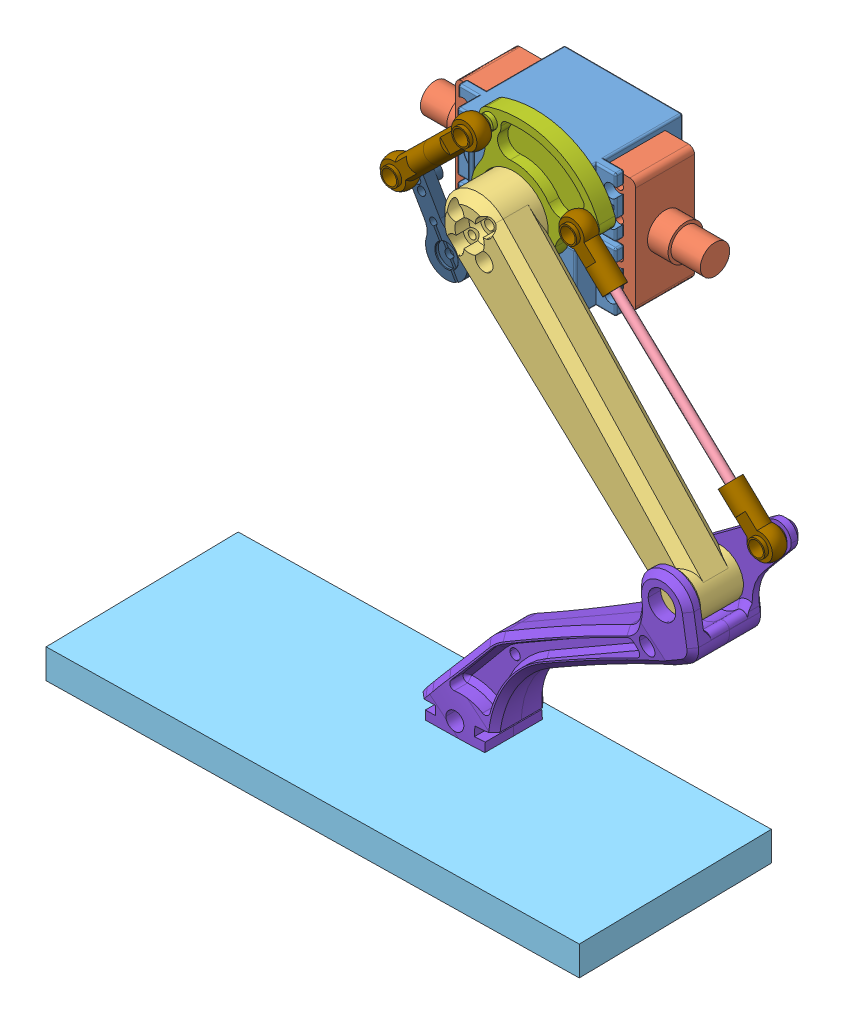
SolidWorks assembly test, configuration Default. Lengths in mm.
Overall size (210.82 208.45 93.67).
15 component instances, 10 part files, 35 mates.
Components (placement in the parent):
- Servo MG996R-1: Servo MG996R [Predeterminado] at (-30.3678 43.9718 31.47) x (1 0 0) z (0 -1 0) size (53.6 47.6 20)
- Servo MG996R-2: Servo MG996R [Predeterminado] at (9.9322 85.9718 31.47) x (-1 0 0) z (0 1 0) size (53.6 47.6 20)
- m_servo_siding-1: m_servo_siding [Default] at (15.4322 64.9718 38.07) size (27 39 20)
- m_servo_siding-2: m_servo_siding [Default] at (-35.8678 64.9718 38.07) x (-1 0 0) z (0 0 1) size (27 39 20)
- upperleg-2: upperleg [Default] at (88.8454 65.1989 5.4511) x (-0.00634 0.283453 0.958965) z (-0.99975 -0.022362 0) size (39.1 93.25 88.61)
- 74_thread-1: 74_thread [Default] at (84.3185 29.4705 82.3546) x (-0.621098 -0.659068 0.424106) z (-0.290865 -0.308647 -0.905613) size (3 74 3)
- Part1^test-1: Part1^test [Default] at (72.6841 -86.0282 -17.0834) x (-0.017436 0 -0.999848) z (0 -1 0) size (66.55 178.4 10) (virtual)
- circular_horn-2: circular_horn [Default] at (-0.0678 75.9718 77.6046) x (-0.859308 -0.511458 0) z (0.511458 -0.859308 0) size (20 4.5 20)
- my_2order-1: my_2order [Default] at (-0.0678 75.9718 70.1746) x (-0.942139 -0.335224 0) z (0 0 1) size (45.25 42.25 10.43)
- lowerleg_r-1: lowerleg_r [Default] at (92.6802 63.8975 4.4511) x (0.011988 0.28327 0.958965) z (-0.999106 0.042282 0) size (46.27 106.28 105.17)
- ball_joint-1: ball_joint [Default] at (89.4129 24.6697 82.3546) x (-0.685832 -0.72776 0) z (0 0 1) size (10 22 7.5)
- ball_joint-2: ball_joint [Default] at (25.37 85.0229 82.3546) x (-0.685832 -0.72776 0) z (0 0 -1) size (10 22 7.5)
- link3_m-1: link3_m [Default] at (85.0271 26.6006 7.1666) x (0.089359 0.269073 0.958965) z (-0.949034 0.315174 0) size (12.82 26.51 28.54)
- ball_joint-3: ball_joint [Default] at (-32.3678 74.7565 85.42) x (0.700786 -0.713371 0) z (0 0 -1) size (10 22 7.5)
- ball_joint-4: ball_joint [Default] at (-8.1131 98.5832 85.42) x (-0.700786 0.713371 0) z (0 0 -1) size (10 22 7.5)
Mates (geometry in assembly coordinates):
- Coincident17: coincident aligned: plane of Servo MG996R-1 through (-6.7057 61.6867 69.07) normal (0 0 1); plane of Servo MG996R-2 through (-13.7299 68.257 69.07) normal (0 0 1)
- Coincident18: coincident aligned: plane of Servo MG996R-1 through (9.9322 43.9718 68.07) normal (1 0 0); plane of Servo MG996R-2 through (9.9322 85.9718 68.07) normal (1 0 0)
- Width3: width anti-aligned: plane of Servo MG996R-2 through (9.9322 65.9718 68.07) normal (0 -1 0); plane of Servo MG996R-1 through (-30.3678 63.9718 68.07) normal (0 1 0); plane of m_servo_siding-1 through (10.4322 84.4718 58.07) normal (0 1 0); plane of m_servo_siding-1 through (10.4322 45.4718 58.07) normal (0 -1 0)
- Coincident19: coincident anti-aligned: plane of Servo MG996R-2 through (16.5822 85.9718 58.07) normal (0 0 -1); plane of m_servo_siding-1 through (18.4322 82.4718 58.07) normal (0 0 1)
- Coincident22: coincident aligned: plane of m_servo_siding-1 through (10.4322 84.4718 58.07) normal (0 1 0); plane of m_servo_siding-2 through (-30.8678 84.4718 58.07) normal (0 1 0)
- Coincident23: coincident aligned: plane of m_servo_siding-1 through (18.4322 82.4718 58.07) normal (0 0 1); plane of m_servo_siding-2 through (-38.8678 47.4718 58.07) normal (0 0 1)
- Concentric16: concentric aligned: cylinder of Servo MG996R-2 through (-35.3678 80.4718 58.07) axis (0 0 1) radius 2.22; cylinder of m_servo_siding-2 through (-35.3678 80.4718 46.07) axis (0 0 1) radius 1.35
- Concentric17: concentric aligned: cylinder of Servo MG996R-1 through (-35.3678 49.4718 58.07) axis (0 0 1) radius 2.22; cylinder of m_servo_siding-2 through (-35.3678 49.4718 46.07) axis (0 0 1) radius 1.35
- Concentric18: concentric aligned: cylinder of Servo MG996R-1 through (14.9322 49.4718 58.07) axis (0 0 1) radius 2.22; cylinder of m_servo_siding-1 through (14.9322 49.4718 46.07) axis (0 0 1) radius 1.35
- Concentric19: concentric aligned: cylinder of Servo MG996R-2 through (14.9322 80.4718 58.07) axis (0 0 1) radius 2.22; cylinder of m_servo_siding-1 through (14.9322 80.4718 46.07) axis (0 0 1) radius 1.35
- Concentric25: concentric anti-aligned: cylinder of Servo MG996R-2 through (-0.0678 75.9718 79.07) axis (0 0 -1) radius 3.592; cylinder of circular_horn-2 through (-0.0678 75.9718 73.1046) axis (0 0 1) radius 4.625
- Coincident24: coincident aligned: plane of Servo MG996R-2 through (-0.9452 79.455 73.1046) normal (0 0 -1); plane of circular_horn-2 through (-0.0678 75.9718 73.1046) normal (0 0 -1)
- Concentric26: concentric anti-aligned: cylinder of circular_horn-2 through (-0.0678 75.9718 75.6046) axis (0 0 1) radius 10; cylinder of my_2order-1 through (-0.0678 75.9718 75.6046) axis (0 0 -1) radius 14.5
- Coincident28: coincident anti-aligned: plane of circular_horn-2 through (-0.0678 75.9718 75.6046) normal (0 0 -1); plane of my_2order-1 through (-0.0678 75.9718 75.6046) normal (0 0 1)
- Concentric27: concentric anti-aligned: cylinder of upperleg-2 through (70.6429 5.2612 94.1046) axis (0 0 -1) radius 8; cylinder of lowerleg_r-1 through (70.6429 5.2612 73.6199) axis (0 0 1) radius 4.7
- Width4: width aligned: plane of lowerleg_r-1 through (70.6429 5.2612 78.6046) normal (0 0 1); plane of upperleg-2 through (70.6429 5.2612 95.1046) normal (0 0 -1); plane of lowerleg_r-1 through (-0.0678 75.9718 94.1046) normal (0 0 1); plane of upperleg-2 through (-0.0678 75.9718 79.6046) normal (0 0 -1)
- Concentric28: concentric aligned: cylinder of upperleg-2 through (-0.0678 75.9718 94.1046) axis (0 0 -1) radius 11.5; cylinder of my_2order-1 through (-0.0678 75.9718 79.1046) axis (0 0 -1) radius 11.75
- Coincident29: coincident anti-aligned: plane of upperleg-2 through (-0.0678 75.9718 75.6046) normal (0 0 -1); plane of my_2order-1 through (-0.0678 75.9718 75.6046) normal (0 0 1)
- Concentric29: concentric anti-aligned: cylinder of 74_thread-1 through (30.4643 80.2221 82.3546) axis (0.72776 -0.685832 0) radius 1.5; cylinder of ball_joint-1 through (89.4128 24.6697 82.3546) axis (-0.72776 0.685832 0) radius 3.5
- Coincident30: coincident anti-aligned: plane of 74_thread-1 through (84.3185 29.4705 82.3546) normal (0.72776 -0.685832 0); plane of ball_joint-1 through (84.3185 29.4705 82.3546) normal (-0.72776 0.685832 0)
- Concentric30: concentric anti-aligned: cylinder of lowerleg_r-1 through (89.4128 24.6697 37.409) axis (0 0 1) radius 4.5; cylinder of ball_joint-1 through (89.4128 24.6697 86.1046) axis (0 0 -1) radius 3
- Coincident31: coincident anti-aligned: plane of lowerleg_r-1 through (70.6429 5.2612 78.6046) normal (0 0 1); plane of ball_joint-1 through (89.4128 24.6697 78.6046) normal (0 0 -1)
- Concentric31: concentric aligned: cylinder of 74_thread-1 through (30.4643 80.2221 82.3546) axis (0.72776 -0.685832 0) radius 1.5; cylinder of ball_joint-2 through (25.37 85.0229 82.3546) axis (0.72776 -0.685832 0) radius 3.5
- Coincident32: coincident anti-aligned: plane of 74_thread-1 through (30.4643 80.2221 82.3546) normal (-0.72776 0.685832 0); plane of ball_joint-2 through (30.4643 80.2221 82.3546) normal (0.72776 -0.685832 0)
- Concentric32: concentric aligned: cylinder of my_2order-1 through (25.37 85.0229 79.1046) axis (0 0 -1) radius 1.35; cylinder of ball_joint-2 through (25.37 85.0229 87.3546) axis (0 0 -1) radius 2.5
- Coincident33: coincident anti-aligned: plane of Servo MG996R-1 through (-20.3678 53.9718 79.07) normal (0 0 1); plane of link3_m-1 through (-20.3678 53.9718 79.07) normal (0 0 -1)
- Concentric33: concentric anti-aligned: cylinder of Servo MG996R-1 through (-20.3678 53.9718 79.07) axis (0 0 -1) radius 3.592; cylinder of link3_m-1 through (-20.3678 53.9718 78.02) axis (0 0 1) radius 7.15
- Coincident34: coincident anti-aligned: circle of ball_joint-3; circle of ball_joint-4
- Concentric34: concentric aligned: cylinder of my_2order-1 through (-8.1131 98.5832 79.1046) axis (0 0 -1) radius 1.35; cylinder of ball_joint-4 through (-8.1131 98.5832 90.42) axis (0 0 -1) radius 2.5
- Concentric35: concentric anti-aligned: cylinder of link3_m-1 through (-32.3678 74.7565 68.9511) axis (0 0 1) radius 1.25; cylinder of ball_joint-3 through (-32.3678 74.7565 90.42) axis (0 0 -1) radius 2.5
- Coincident36: coincident anti-aligned: plane of link3_m-1 through (-32.3678 74.7565 81.67) normal (0 0 1); plane of ball_joint-3 through (-32.3678 74.7565 81.67) normal (0 0 -1)
- Angle1: planar angle = 2.356194 rad: plane of upperleg-2 through (8.3436 83.814 94.1046) normal (0.731422 0.681925 0); plane of Servo MG996R-2 through (9.9322 85.9718 68.07) normal (0 1 0)
- Angle2: planar angle = 1.047198 rad: plane of link3_m-1 through (-29.7697 76.2565 78.02) normal (0.866025 0.5 0); plane of Servo MG996R-2 through (9.9322 85.9718 68.07) normal (0 1 0)
- Angle3: planar angle = 2.356194 rad: plane of upperleg-2 through (50.7299 27.0834 5.4511) normal (-0.707107 -0.707107 0); plane of Servo MG996R-2 through (9.9322 85.9718 68.07) normal (0 1 0)
- Angle4: planar angle = 1.047198 rad: plane of link3_m-1 through (-29.7697 76.2565 78.02) normal (0.866025 0.5 0); plane of Servo MG996R-2 through (9.9322 85.9718 68.07) normal (0 1 0)
